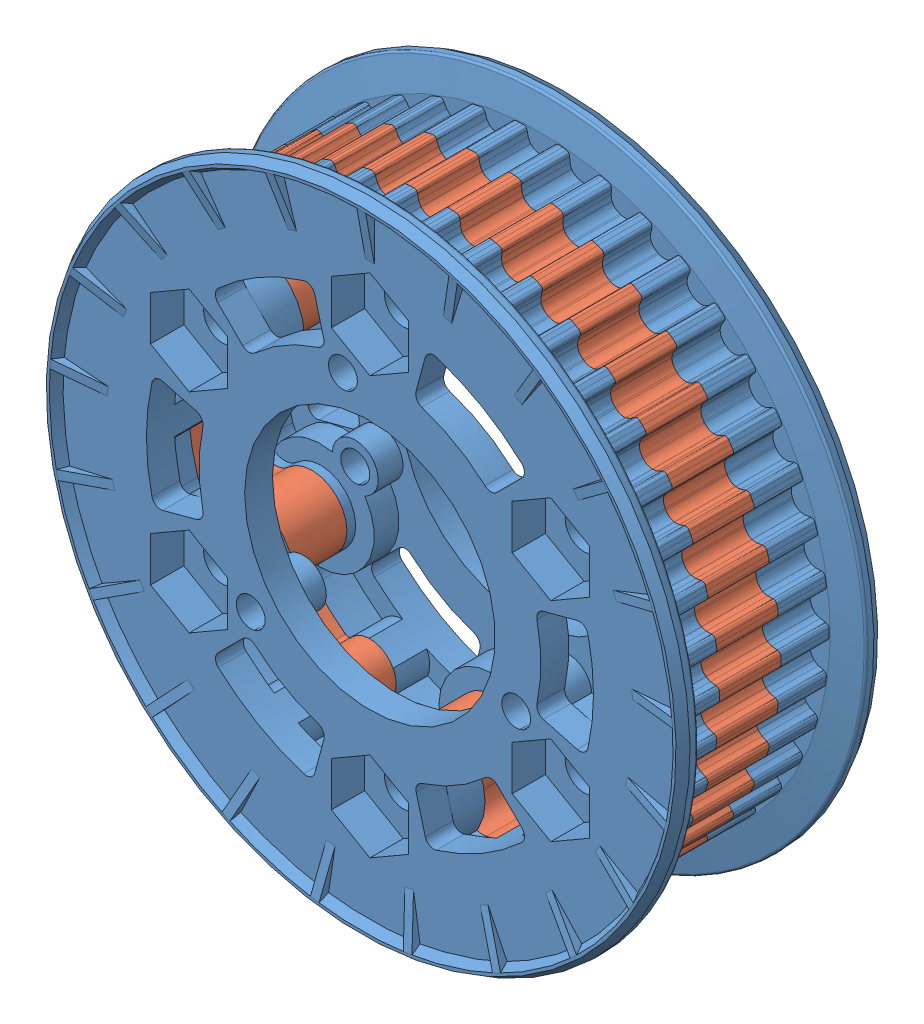
SolidWorks assembly 217-3199-STEP, configuration Default. Lengths in mm.
Overall size (73 73 23.01).
3 component instances, 2 part files, 0 mates.
Components (placement in the parent):
- 217-3199-001 Rev4-1: 217-3199-001 Rev4 [Default] at origin size (73 73 11.51)
- 217-3199-001 Rev4-2: 217-3199-001 Rev4 [Default] at (0 0 -17.825) x (-1 0 0) z (0 0 -1) size (73 73 11.51)
- 217-3199-002 Rev3-1: 217-3199-002 Rev3 [Default] at (0 0 -5.5) x (-1 0 0) z (0 0 1) size (65.74 65.61 14)
